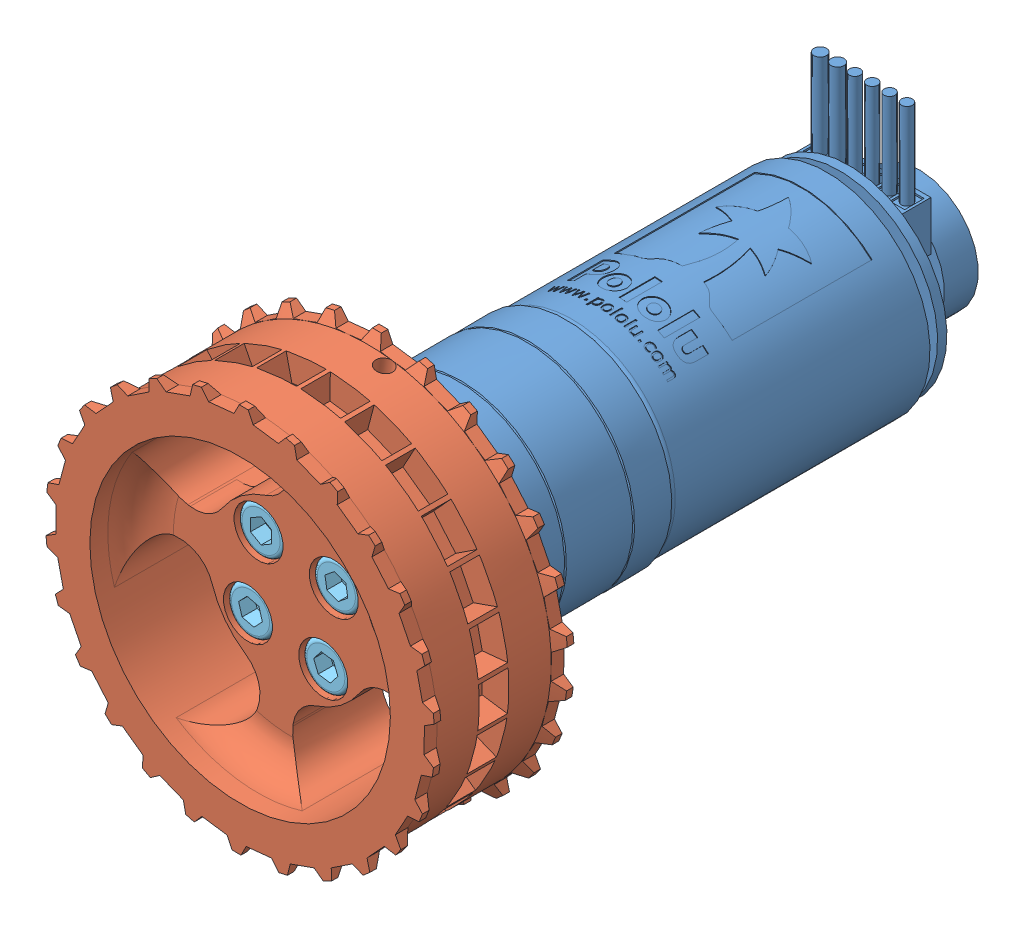
SolidWorks assembly wheel-powered, configuration Default. Lengths in mm.
Overall size (51.92 51.74 81).
8 component instances, 5 part files, 19 mates.
Components (placement in the parent):
- wheel-motor-1: wheel-motor [Default] at (-36.8745 16.797 -18.375) x (0.990268 -0.139173 0) z (0 0 1) size (25 32.85 72)
- wheel-body-1: wheel-body [Powered Visual] at (-6.3 12.5 5) x (0.990268 -0.139173 0) z (0 0 1) size (46 45.78 16.5)
- wheel-motor-mount-1: wheel-motor-mount [Default] at (-6.3 12.5 5) x (0.990268 -0.139173 0) z (-0.139173 -0.990268 0) size (19 5 19)
- M2.5-6mm-scrub-1: M2.5-6mm-scrub [Default] at (-6.0912 13.9854 7.5) x (0.990268 -0.139173 0) z (0 0 1) size (3.05 6.18 3.38)
- M3-8mm-bolt-1: M3-8mm-bolt [Default] at (-10.1215 17.5713 15.2) x (1 0 0) z (0 1 0) size (5.5 10.77 5.5)
- M3-8mm-bolt-2: M3-8mm-bolt [Default] at (-1.2287 16.3215 15.2) x (0.987351 0.158553 0) z (-0.158553 0.987351 0) size (5.5 10.77 5.5)
- M3-8mm-bolt-4: M3-8mm-bolt [Default] at (-11.3713 8.6785 15.2) x (0.959125 0.282984 0) z (-0.282984 0.959125 0) size (5.5 10.77 5.5)
- M3-8mm-bolt-6: M3-8mm-bolt [Default] at (-2.4785 7.4287 15.2) x (0.928571 0.371154 0) z (-0.371154 0.928571 0) size (5.5 10.77 5.5)
Mates (geometry in assembly coordinates):
- Coincident1: coincident: plane of wheel-motor-1 through (-6.3 12.5 0) normal (0 0 1); plane of assembly through (0 0 0) normal (0 0 1)
- Tangent1: tangent: cylinder of wheel-motor-1 through (-6.3 12.5 -17) axis (0 0 1) radius 12.5; plane of assembly through (0 0 0) normal (0 1 0)
- Coincident2: coincident aligned: plane of wheel-motor-1 through (0 22.2401 -53.8) normal (1 0 0); plane of assembly through (0 0 0) normal (1 0 0)
- Concentric1: concentric anti-aligned: cylinder of wheel-motor-1 through (-6.3 12.5 0) axis (0 0 1) radius 2; cylinder of wheel-motor-mount-1 through (-6.3 12.5 10) axis (0 0 -1) radius 2
- Parallel1: parallel aligned: plane of wheel-motor-1 through (-6.0912 13.9854 4.5) normal (0.139173 0.990268 0); plane of wheel-motor-mount-1
- Distance1: distance = 0.5 mm anti-aligned: plane of wheel-motor-1 through (-6.3 12.5 4.5) normal (0 0 1); plane of wheel-motor-mount-1 through (-6.3 12.5 5) normal (0 0 -1)
- Concentric2: concentric anti-aligned: cylinder of wheel-motor-mount-1 through (-7.6223 3.0915 7.5) axis (0.139173 0.990268 0) radius 1.225; cylinder of M2.5-6mm-scrub-1 through (-5.2562 19.927 7.5) axis (-0.139173 -0.990268 0) radius 1.465
- Coincident5: coincident anti-aligned: plane of wheel-motor-1 through (-6.0912 13.9854 4.5) normal (0.139173 0.990268 0); plane of M2.5-6mm-scrub-1 through (-6.0912 13.9854 7.5) normal (-0.139173 -0.990268 0)
- Concentric3: concentric aligned: cylinder of wheel-body-1 through (-10.1215 17.5713 21.501) axis (0 0 -1) radius 1.9; cylinder of wheel-motor-mount-1 through (-10.1215 17.5713 10) axis (0 0 -1) radius 1.425
- Concentric7: concentric aligned: cylinder of wheel-body-1 through (-2.4785 7.4287 21.501) axis (0 0 -1) radius 1.9; cylinder of wheel-motor-mount-1 through (-2.4785 7.4287 10) axis (0 0 -1) radius 1.425
- Coincident6: coincident anti-aligned: plane of wheel-body-1 through (-6.3 12.5 10) normal (0 0 -1); plane of wheel-motor-mount-1 through (-6.3 12.5 10) normal (0 0 1)
- Concentric8: concentric anti-aligned: cylinder of wheel-motor-mount-1 through (-10.1215 17.5713 10) axis (0 0 -1) radius 1.425; cylinder of M3-8mm-bolt-1 through (-10.1215 17.5713 4.43) axis (0 0 1) radius 1.475
- Coincident7: coincident anti-aligned: plane of wheel-body-1 through (-10.1215 17.5713 12.25) normal (0 0 1); plane of M3-8mm-bolt-1 through (-10.1215 17.5713 12.25) normal (0 0 -1)
- Concentric9: concentric anti-aligned: cylinder of wheel-motor-mount-1 through (-1.2287 16.3215 10) axis (0 0 -1) radius 1.425; cylinder of M3-8mm-bolt-2 through (-1.2287 16.3215 4.43) axis (0 0 1) radius 1.475
- Coincident8: coincident anti-aligned: plane of wheel-body-1 through (-1.2287 16.3215 12.25) normal (0 0 1); plane of M3-8mm-bolt-2 through (-1.2287 16.3215 12.25) normal (0 0 -1)
- Concentric10: concentric anti-aligned: cylinder of wheel-motor-mount-1 through (-11.3713 8.6785 10) axis (0 0 -1) radius 1.425; cylinder of M3-8mm-bolt-4 through (-11.3713 8.6785 4.43) axis (0 0 1) radius 1.475
- Coincident9: coincident anti-aligned: plane of wheel-body-1 through (-11.3713 8.6785 12.25) normal (0 0 1); plane of M3-8mm-bolt-4 through (-11.3713 8.6785 12.25) normal (0 0 -1)
- Concentric11: concentric anti-aligned: cylinder of wheel-motor-mount-1 through (-2.4785 7.4287 10) axis (0 0 -1) radius 1.425; cylinder of M3-8mm-bolt-6 through (-2.4785 7.4287 4.43) axis (0 0 1) radius 1.475
- Coincident10: coincident anti-aligned: plane of wheel-body-1 through (-2.4785 7.4287 12.25) normal (0 0 1); plane of M3-8mm-bolt-6 through (-2.4785 7.4287 12.25) normal (0 0 -1)
